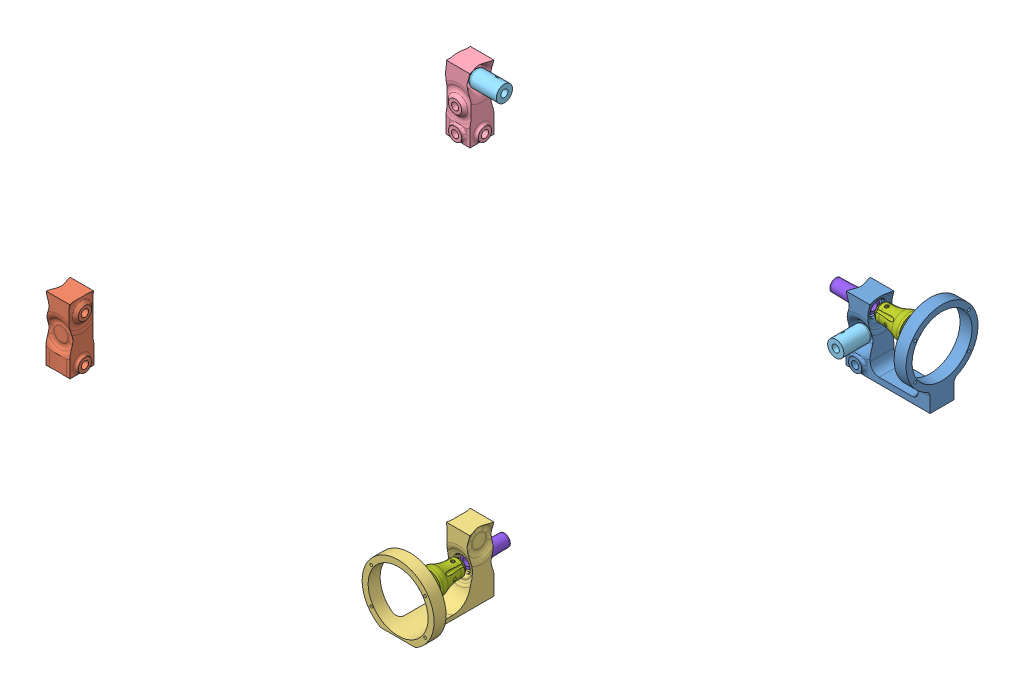
SolidWorks assembly full asem, configuration Default. Lengths in mm.
Overall size (813.2 147.58 847.33).
12 component instances, 8 part files, 24 mates.
Components (placement in the parent):
- cornerPieceXY1WithMotorMount-1: cornerPieceXY1WithMotorMount [Default] at (-4.5523 77.6484 96.7429) size (145 147.58 120)
- cornerPieceForXY3-1: cornerPieceForXY3 [Default] at (-671.8866 77.6484 764.0772) size (47.86 107.08 48.14)
- cornerPieceForXY4withMotorMount-1: cornerPieceForXY4withMotorMount [Default] at (-4.5523 77.6484 804.0772) x (-1 0 0) z (0 0 -1) size (120 112.58 145)
- cornerPieceForXY2-2: cornerPieceForXY2 [Default] at (-671.8866 77.6484 136.7429) x (-1 0 0) z (0 0 -1) size (48.88 107.08 51.28)
- bearingToThreadedRodCouplerLongerV2Part1-1: bearingToThreadedRodCouplerLongerV2Part1 [Default] at (-662.7523 95.1484 116.7429) x (0 0.44584 0.895112) z (1 0 0) size (27 27 58.2)
- bearingToThreadedRodCouplerLongerV2SecondPart-1: bearingToThreadedRodCouplerLongerV2SecondPart [Default] at (-677.7523 95.1484 116.7429) x (0 0.614698 -0.788762) z (0 0.788762 0.614698) size (16 25 16)
- Bearing20ThreadedRodCouplerV2-1: Bearing20ThreadedRodCouplerV2 [Default] at (55.4477 95.1484 116.7429) x (0 -0.153309 0.988178) z (1 0 0) size (42.43 42.43 52.92)
- Bearing20ThreadedRodCoupler-2: Bearing20ThreadedRodCoupler [Default] at (-4.5523 60.1484 691.9429) x (-0.996984 -0.077604 0) z (0 0 -1) size (24 24 63)
- Bearing20ThreadedRodCoupler-3: Bearing20ThreadedRodCoupler [Default] at (-96.6866 95.1484 116.7429) x (0 0.213329 -0.97698) z (-1 0 0) size (24 24 63)
- bearingToThreadedRodCouplerLongerV2Part1-2: bearingToThreadedRodCouplerLongerV2Part1 [Default] at (-4.5523 60.1484 125.8772) x (0.869525 0.493889 0) z (0 0 1) size (27 27 58.2)
- bearingToThreadedRodCouplerLongerV2SecondPart-2: bearingToThreadedRodCouplerLongerV2SecondPart [Default] at (-4.5523 60.1484 110.8772) x (-0.275258 0.961371 0) z (-0.961371 -0.275258 0) size (16 25 16)
- Bearing20ThreadedRodCouplerV2-2: Bearing20ThreadedRodCouplerV2 [Default] at (-4.5523 60.1484 844.0772) x (0.995901 -0.09045 0) z (0 0 1) size (42.43 42.43 52.92)
Mates (geometry in assembly coordinates):
- Parallel2: parallel anti-aligned: plane of cornerPieceXY1WithMotorMount-1 through (-4.5523 77.6484 126.7429) normal (0 0 1); plane of cornerPieceForXY4withMotorMount-1 through (-4.5523 77.6484 774.0772) normal (0 0 -1)
- Parallel5: parallel aligned: plane of cornerPieceForXY3-1 through (-671.8866 7.6484 764.0772) normal (0 -1 0); plane of cornerPieceForXY4withMotorMount-1 through (-4.5523 7.6484 804.0772) normal (0 -1 0)
- Parallel6: parallel aligned: plane of cornerPieceXY1WithMotorMount-1 through (-4.5523 7.6484 96.7429) normal (0 -1 0); plane of cornerPieceForXY4withMotorMount-1 through (-4.5523 7.6484 804.0772) normal (0 -1 0)
- Concentric1: concentric anti-aligned: cylinder of cornerPieceForXY3-1 through (-671.8866 20.1484 744.0772) axis (0 0 1) radius 6.075; cylinder of cornerPieceForXY2-2 through (-671.8866 20.1484 141.7429) axis (0 0 -1) radius 6.075
- Concentric2: concentric aligned: cylinder of cornerPieceXY1WithMotorMount-1 through (-24.5523 20.1484 116.7429) axis (1 0 0) radius 6.075; cylinder of cornerPieceForXY2-2 through (-661.8866 20.1484 116.7429) axis (1 0 0) radius 6.075
- Concentric3: concentric anti-aligned: cylinder of cornerPieceXY1WithMotorMount-1 through (-4.5523 20.1484 136.7429) axis (0 0 -1) radius 6.075; cylinder of cornerPieceForXY4withMotorMount-1 through (-4.5523 20.1484 764.0772) axis (0 0 1) radius 6.075
- Concentric4: concentric anti-aligned: cylinder of cornerPieceForXY3-1 through (-661.8866 20.1484 784.0772) axis (1 0 0) radius 6.075; cylinder of cornerPieceForXY4withMotorMount-1 through (-14.5523 20.1484 784.0772) axis (-1 0 0) radius 6.075
- Coincident11: coincident anti-aligned: circle of bearingToThreadedRodCouplerLongerV2Part1-1; circle of bearingToThreadedRodCouplerLongerV2SecondPart-1
- Concentric11: concentric anti-aligned: cylinder of cornerPieceXY1WithMotorMount-1 through (115.4477 95.1484 116.7429) axis (-1 0 0) radius 50; cylinder of Bearing20ThreadedRodCouplerV2-1 through (24.8111 95.1484 116.7429) axis (1 0 0) radius 21.2132
- Concentric12: concentric anti-aligned: cylinder of cornerPieceForXY4withMotorMount-1 through (-4.5523 60.1484 759.0772) axis (0 0 1) radius 13; cylinder of Bearing20ThreadedRodCoupler-2 through (-4.5523 60.1484 796.9429) axis (0 0 -1) radius 10.05
- Coincident16: coincident aligned: circle of cornerPieceXY1WithMotorMount-1; plane of Bearing20ThreadedRodCoupler-3 through (1.3134 106.8722 119.3028) normal (1 0 0)
- Concentric14: concentric anti-aligned: cylinder of cornerPieceXY1WithMotorMount-1 through (-4.5523 60.1484 146.7429) axis (0 0 -1) radius 16.075; cylinder of bearingToThreadedRodCouplerLongerV2Part1-2 through (-4.5523 60.1484 110.8772) axis (0 0 1) radius 6.05
- Coincident18: coincident anti-aligned: circle of bearingToThreadedRodCouplerLongerV2Part1-2; circle of bearingToThreadedRodCouplerLongerV2SecondPart-2
- Concentric16: concentric anti-aligned: cylinder of Bearing20ThreadedRodCoupler-2 through (-4.5523 60.1484 796.9429) axis (0 0 -1) radius 6.25; cylinder of Bearing20ThreadedRodCouplerV2-2 through (-4.5523 60.1484 739.0772) axis (0 0 1) radius 6.25
- Distance2: distance = 50 mm aligned: plane of Bearing20ThreadedRodCouplerV2-2 through (-4.5523 60.1484 854.0772) normal (0 0 1); plane of cornerPieceForXY4withMotorMount-1 through (-4.5523 77.6484 904.0772) normal (0 0 1)
- Coincident21: coincident aligned: circle of cornerPieceForXY4withMotorMount-1; plane of Bearing20ThreadedRodCoupler-2 through (-3.621 48.1846 789.9429) normal (0 0 1)
- Distance3: distance = 700 mm anti-aligned: plane of Bearing20ThreadedRodCouplerV2-1 through (55.4477 95.1484 116.7429) normal (-1 0 0); plane of bearingToThreadedRodCouplerLongerV2Part1-1 through (-644.5523 95.1484 116.7429) normal (1 0 0)
- Distance5: distance = 50 mm aligned: plane of Bearing20ThreadedRodCouplerV2-1 through (65.4477 95.1484 116.7429) normal (1 0 0); plane of cornerPieceXY1WithMotorMount-1 through (115.4477 77.6484 96.7429) normal (1 0 0)
- Distance6: distance = 710 mm aligned: plane of Bearing20ThreadedRodCouplerV2-2 through (-4.5523 60.1484 854.0772) normal (0 0 1); plane of bearingToThreadedRodCouplerLongerV2Part1-2 through (-4.5523 60.1484 144.0772) normal (0 0 1)
- Coincident26: coincident anti-aligned: plane of cornerPieceXY1WithMotorMount-1 through (-4.5523 60.1484 110.8772) normal (0 0 1); circle of bearingToThreadedRodCouplerLongerV2SecondPart-2
- Concentric17: concentric anti-aligned: circle of cornerPieceForXY4withMotorMount-1; circle of Bearing20ThreadedRodCoupler-2
- Concentric18: concentric aligned: circle of cornerPieceForXY2-2; circle of bearingToThreadedRodCouplerLongerV2SecondPart-1
- Coincident27: coincident aligned: plane of cornerPieceForXY2-2 through (-677.7523 77.6484 136.7429) normal (1 0 0); plane of bearingToThreadedRodCouplerLongerV2SecondPart-1 through (-677.7523 95.1484 116.7429) normal (1 0 0)
- Concentric19: concentric anti-aligned: cylinder of cornerPieceXY1WithMotorMount-1 through (-34.5523 95.1484 116.7429) axis (1 0 0) radius 16.075; cylinder of Bearing20ThreadedRodCoupler-3 through (8.3134 95.1484 116.7429) axis (-1 0 0) radius 10.05
